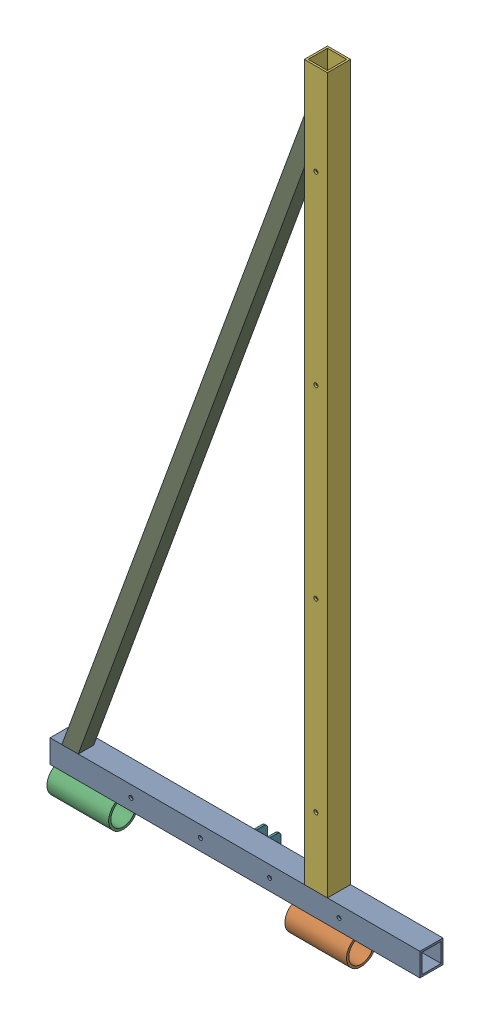
SolidWorks assembly GE-16034_ASM, configuration Default. Lengths in mm.
Overall size (609.6 1267.46 68.58).
9 component instances, 6 part files, 0 mates.
Components (placement in the parent):
- GE-16034-01-1: GE-16034-01 [Default] at origin size (609.6 38.1 38.1)
- GE-16034-02-1: GE-16034-02 [Default] at (138.1125 -46.355 0) x (0 -1 0) z (0 0 1) size (48.26 101.6 48.26)
- GE-16034-02-2: GE-16034-02 [Default] at (-254 -46.355 0) x (0 -1 0) z (0 0 1) size (48.26 101.6 48.26)
- GE-16034-03-1: GE-16034-03 [Default] at (-254 -22.225 0) x (0 0 -1) z (0 1 0) size (12.7 101.6 3.17)
- GE-16034-03-2: GE-16034-03 [Default] at (138.1125 -22.225 0) x (0 0 -1) z (0 1 0) size (12.7 101.6 3.17)
- GE-16034-04-1: GE-16034-04 [Default] at (133.35 608.0125 0) x (0 -1 0) z (1 0 0) size (1177.93 38.1 38.1)
- GE-16034-05-1: GE-16034-05 [Default] at (0 0 -19.05) x (0 1 0) z (0 0 1) size (25.4 25.4 25.4)
- GE-16034-05-2: GE-16034-05 [Default] at (101.6 0 -19.05) x (0 1 0) z (0 0 1) size (25.4 25.4 25.4)
- GE-16034-06-1: GE-16034-06 [Default] at (-73.5741 563.6748 6.35) x (0.34202 0.939693 0) z (0 0 -1) size (1168.4 25.4 25.4)
